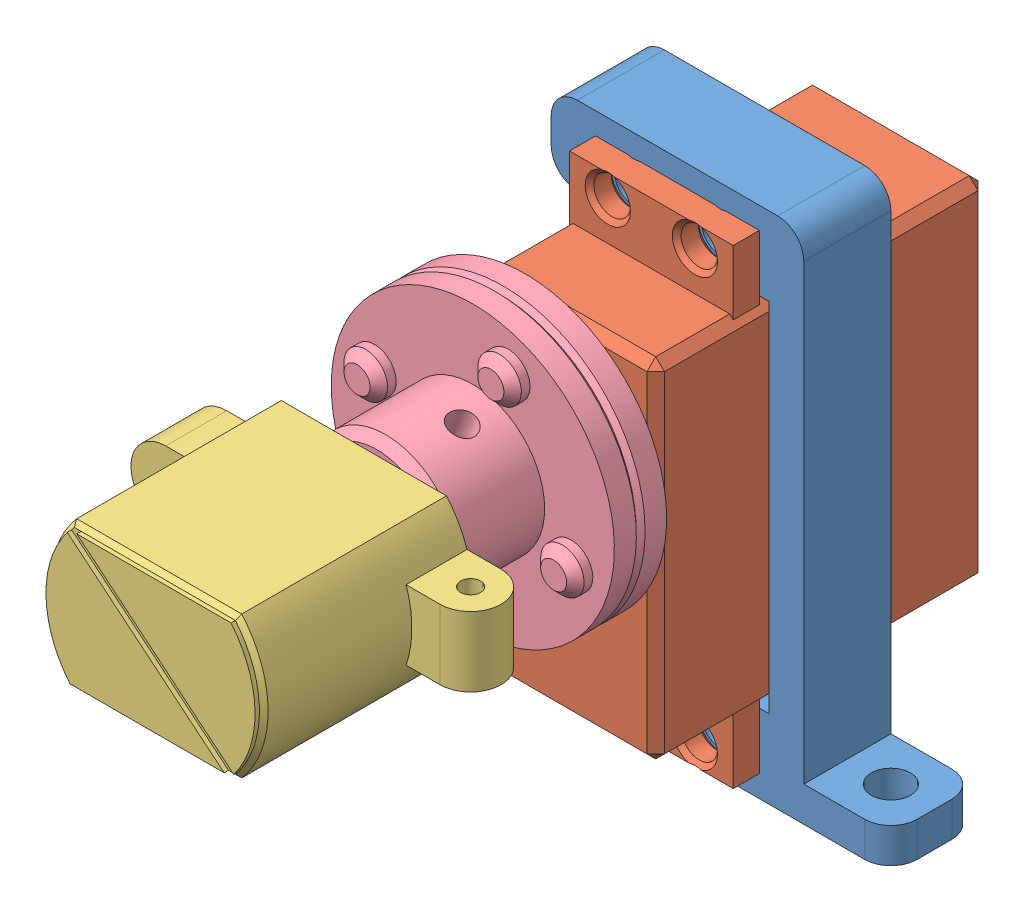
SolidWorks assembly 舵机组合, configuration 默认. Lengths in mm.
Overall size (49 60.81 86).
4 component instances, 4 part files, 8 mates.
Components (placement in the parent):
- 舵机连接件-1: 舵机连接件 [默认] at (-65.8222 -4.5425 -5) size (49 59 10)
- 35kg舵机-1: 35kg舵机 [默认] at (-65.8222 5.9575 17.5) x (0 1 0) z (1 0 0) size (54 43 20)
- magswitch-1: magswitch [默认] at (-65.8222 5.9575 41) x (0 0 1) z (-1 0 0) size (35.5 16.3 39)
- 舵盘联轴器-1: 舵盘联轴器 [默认] at (-65.8222 5.9575 17.5) x (0.940481 -0.339847 0) z (0 0 1) size (32.5 32.5 22)
Mates (geometry in assembly coordinates):
- 重合1: coincident anti-aligned: plane of 舵机连接件-1 through (-65.8222 -4.5425 5) normal (0 0 1); plane of 35kg舵机-1 through (-65.8222 5.9575 5) normal (0 0 -1)
- 同心1: concentric anti-aligned: cylinder of 舵机连接件-1 through (-70.8222 19.9575 5) axis (0 0 -1) radius 2.25; cylinder of 35kg舵机-1 through (-70.8222 19.9575 5) axis (0 0 1) radius 2.1
- 同心2: concentric anti-aligned: cylinder of 舵机连接件-1 through (-60.8222 19.9575 5) axis (0 0 -1) radius 2.25; cylinder of 35kg舵机-1 through (-60.8222 19.9575 5) axis (0 0 1) radius 2.1
- 距离1: distance = 23.5 mm anti-aligned: plane of magswitch-1 through (-65.8222 5.9575 41) normal (0 0 -1); plane of 35kg舵机-1 through (-65.8222 5.9575 17.5) normal (0 0 1)
- 同心3: concentric anti-aligned: cylinder of 35kg舵机-1 through (-65.8222 5.9575 22.5) axis (0 0 -1) radius 2.9; cylinder of magswitch-1 through (-65.8222 5.9575 30) axis (0 0 1) radius 3.1
- 平行1: parallel aligned: plane of 35kg舵机-1 through (-55.8222 15.4575 -20.5) normal (0 1 0); plane of magswitch-1 through (-56.3445 14.1075 65) normal (0 1 0)
- 同心4: concentric anti-aligned: cylinder of magswitch-1 through (-65.8222 5.9575 30) axis (0 0 1) radius 3.1; cylinder of 舵盘联轴器-1 through (-65.8222 5.9575 17.5) axis (0 0 -1) radius 3.25
- 重合3: coincident anti-aligned: plane of 35kg舵机-1 through (-65.8222 5.9575 17.5) normal (0 0 1); plane of 舵盘联轴器-1 through (-64.7177 9.0141 17.5) normal (0 0 -1)
